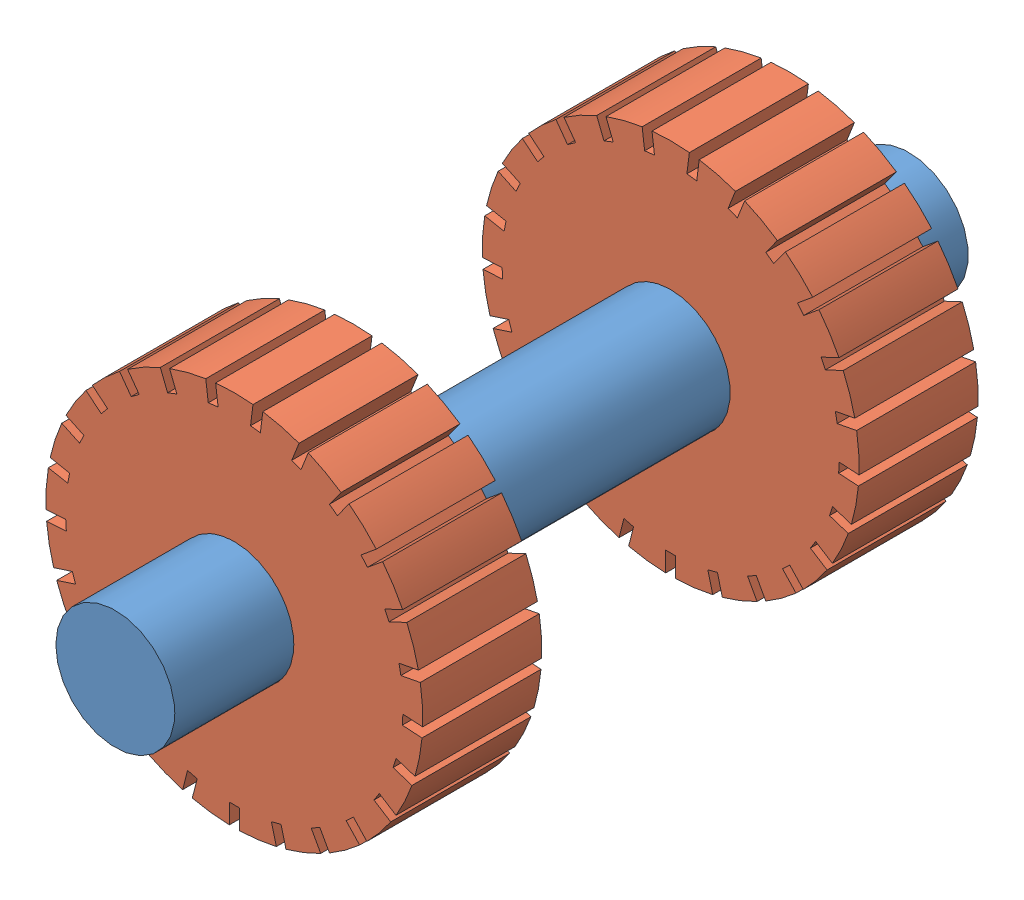
SolidWorks assembly Assem1, configuration Default. Lengths in mm.
Overall size (120.65 120.63 254).
3 component instances, 2 part files, 4 mates.
Components (placement in the parent):
- Rod2-1: Rod2 [Default] at origin size (38.1 38.1 254)
- Roller 2-2: Roller 2 [Default] at (0 0 76.2) x (1 0 0) z (0 1 0) size (120.65 38.1 120.63)
- Roller 2-5: Roller 2 [Default] at (0 0 215.9) x (1 0 0) z (0 1 0) size (120.65 38.1 120.63)
Mates (geometry in assembly coordinates):
- Concentric1: concentric anti-aligned: cylinder of Rod2-1 through (0 0 254) axis (0 0 -1) radius 19.05; cylinder of Roller 2-2 through (0 0 38.1) axis (0 0 1) radius 19.05
- Distance2: distance = 76.2 mm anti-aligned: plane of Roller 2-2 through (0 0 76.2) normal (0 0 1); plane of Rod2-1 through (0 0 0) normal (0 0 -1)
- Concentric2: concentric: cylinder of Rod2-1 through (0 0 254) axis (0 0 -1) radius 19.05; cylinder of Roller 2-5 through (0 0 177.8) axis (0 0 1) radius 19.05
- Distance3: distance = 177.8 mm aligned: plane of Rod2-1 through (0 0 0) normal (0 0 -1); plane of Roller 2-5 through (0 0 177.8) normal (0 0 -1)
